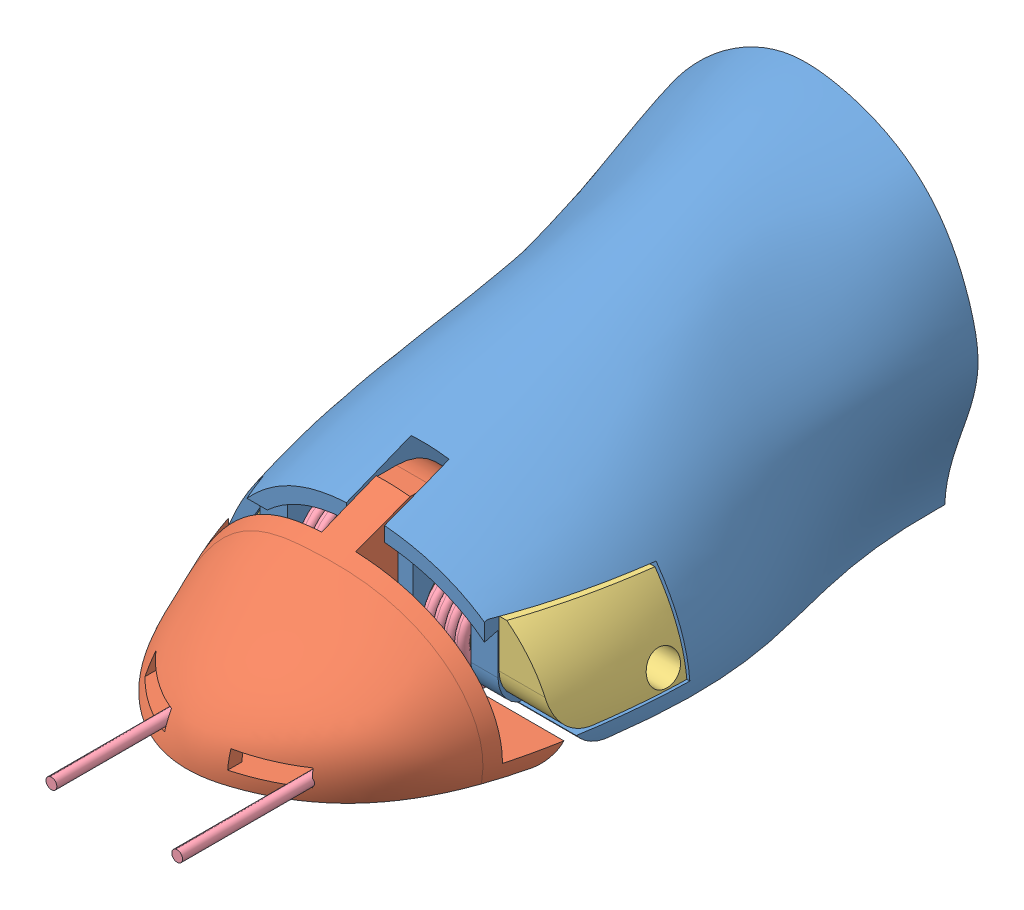
SolidWorks assembly toes, configuration Défaut. Lengths in mm.
Overall size (157.44 76.37 151.6).
5 component instances, 4 part files, 9 mates.
Components (placement in the parent):
- ankle-1: ankle [Défaut] at (-55.0738 -16.0193 126.056) size (157.39 74.93 151.55)
- toes-1: toes [Défaut] at (-55.0238 -16.0615 126.0612) x (1 0 0) z (0 0.000658 1) size (157.39 76.27 151.55)
- axe_toes-1: axe_toes [Défaut] at (-56.6738 -8.1193 190.256) x (0 0 -1) z (1 0 0) size (18.24 15.68 53.53)
- ressort_G_121_160_0400_0-1: ressort_G_121_160_0400_0 [Default] at (-62.4738 -8.1193 190.256) x (0 -1 0.000763) z (-1 0 0) size (12.11 46.8 8.11)
- ressort_G_121_160_0400_0-2: ressort_G_121_160_0400_0 [Default] at (-43.9738 -8.1193 190.256) x (0 -1 0.000763) z (-1 0 0) size (12.11 46.8 8.11)
Mates (geometry in assembly coordinates):
- Concentric1: concentric anti-aligned: cylinder of ankle-1 through (-39.9359 -8.1193 190.256) axis (-1 0 0) radius 4.15; cylinder of toes-1 through (-70.8618 -8.1193 190.256) axis (1 0 0) radius 4.15
- Distance1: distance = 0.25 mm anti-aligned: plane of toes-1 through (-54.1238 31.0211 194.2303) normal (1 0 0); plane of ankle-1 through (-53.8738 31.0242 176.256) normal (-1 0 0)
- Concentric2: concentric aligned: cylinder of toes-1 through (-70.8618 -8.1193 190.256) axis (1 0 0) radius 4.15; cylinder of axe_toes-1 through (-69.9738 -8.1193 190.256) axis (1 0 0) radius 3.9
- Coincident1: coincident anti-aligned: plane of ankle-1 through (-39.1738 31.0242 196.256) normal (1 0 0); plane of axe_toes-1 through (-39.1738 -8.1193 190.256) normal (-1 0 0)
- Parallel1: parallel anti-aligned: plane of ankle-1 through (-26.3271 -1.2193 198.256) normal (0 -1 0); plane of axe_toes-1 through (-28.6738 -1.6193 196.106) normal (0 1 0)
- Concentric3: concentric anti-aligned: cylinder of axe_toes-1 through (-69.9738 -8.1193 190.256) axis (1 0 0) radius 3.9; line of ressort_G_121_160_0400_0-1 through (-62.4738 -8.1193 190.256) axis (-1 0 0)
- Tangent3: tangent anti-aligned: plane of ankle-1 through (-61.6738 31.0242 176.256) normal (-1 0 0); cylinder of ressort_G_121_160_0400_0-1 through (-62.4738 -13.3509 214.34) axis (0 0.000763 1) radius 0.8
- Concentric6: concentric anti-aligned: cylinder of axe_toes-1 through (-69.9738 -8.1193 190.256) axis (1 0 0) radius 3.9; line of ressort_G_121_160_0400_0-2 through (-43.9738 -8.1193 190.256) axis (-1 0 0)
- Tangent4: tangent anti-aligned: plane of ankle-1 through (-43.1738 31.0242 176.256) normal (-1 0 0); cylinder of ressort_G_121_160_0400_0-2 through (-43.9738 -13.3509 214.34) axis (0 0.000763 1) radius 0.8
